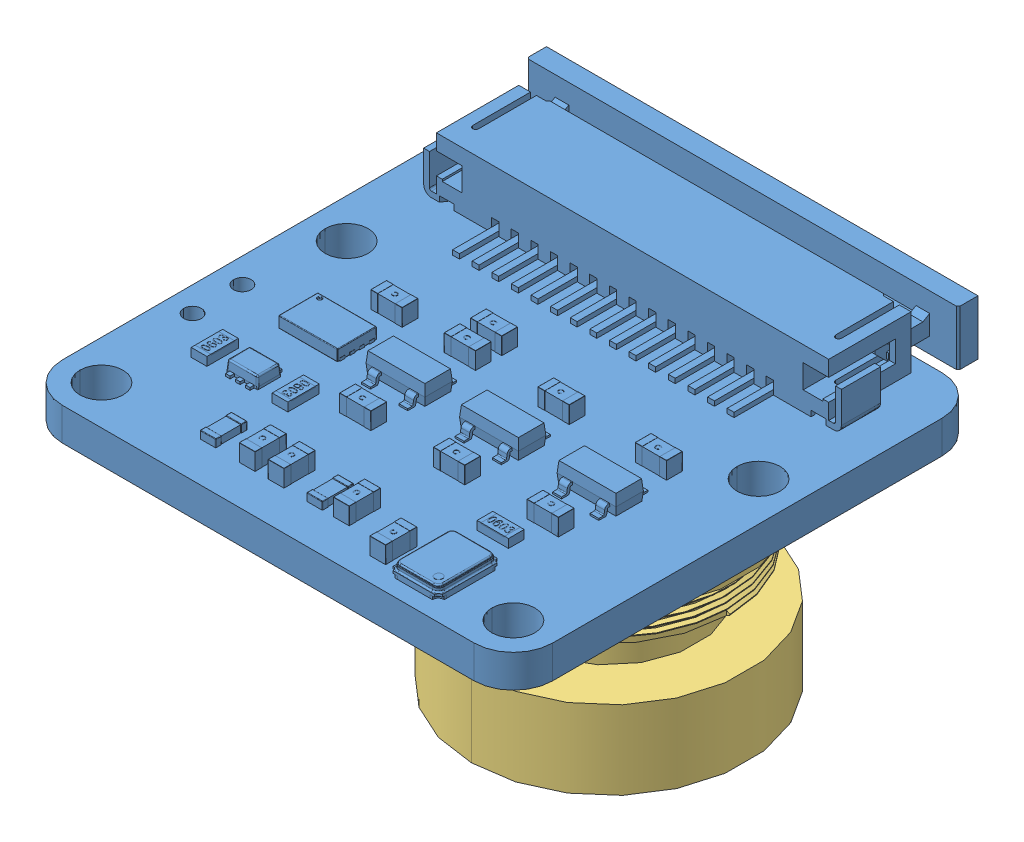
SolidWorks assembly IMX219 with Wide Angle Lens, configuration Default. Lengths in mm.
Overall size (25 18.46 25.27).
5 component instances, 4 part files, 0 mates.
Components (placement in the parent):
- UC-609(B0179&B0193)^IMX219 with Wide Angle Lens-1: UC-609(B0179&B0193)^IMX219 with Wide Angle Lens [Default] at origin size (25 18.46 25.27) (virtual)
  - UC-609^UC-609(B0179&B0193)_IMX219 with Wide Angle Lens-1: UC-609^UC-609(B0179&B0193)_IMX219 with Wide Angle Lens [Default] at (-10.5 -2.393 60.775) x (1 0 0) z (0 -1 0) size (25 28.67 5.64) (virtual)
  - 15pin __15cm__FPC^UC-609(B0179&B0193)_IMX219 with Wide Angle Lens-1: 15pin __15cm__FPC^UC-609(B0179&B0193)_IMX219 with Wide Angle Lens [Default] at origin (suppressed, hidden, virtual)
  - 9^UC-609(B0179&B0193)_IMX219 with Wide Angle Lens-1: 9^UC-609(B0179&B0193)_IMX219 with Wide Angle Lens [Default] at (-0.48 -3.4676 60.435) x (-1 0 0) z (0 0 1) size (9.3 0.9 7.5) (virtual)
  - 8^UC-609(B0179&B0193)_IMX219 with Wide Angle Lens-1: 8^UC-609(B0179&B0193)_IMX219 with Wide Angle Lens [Default] at (-0.5 -2.493 60.663) x (-1 0 0) z (0 0 1) size (14 13.8 14.25) (virtual)
